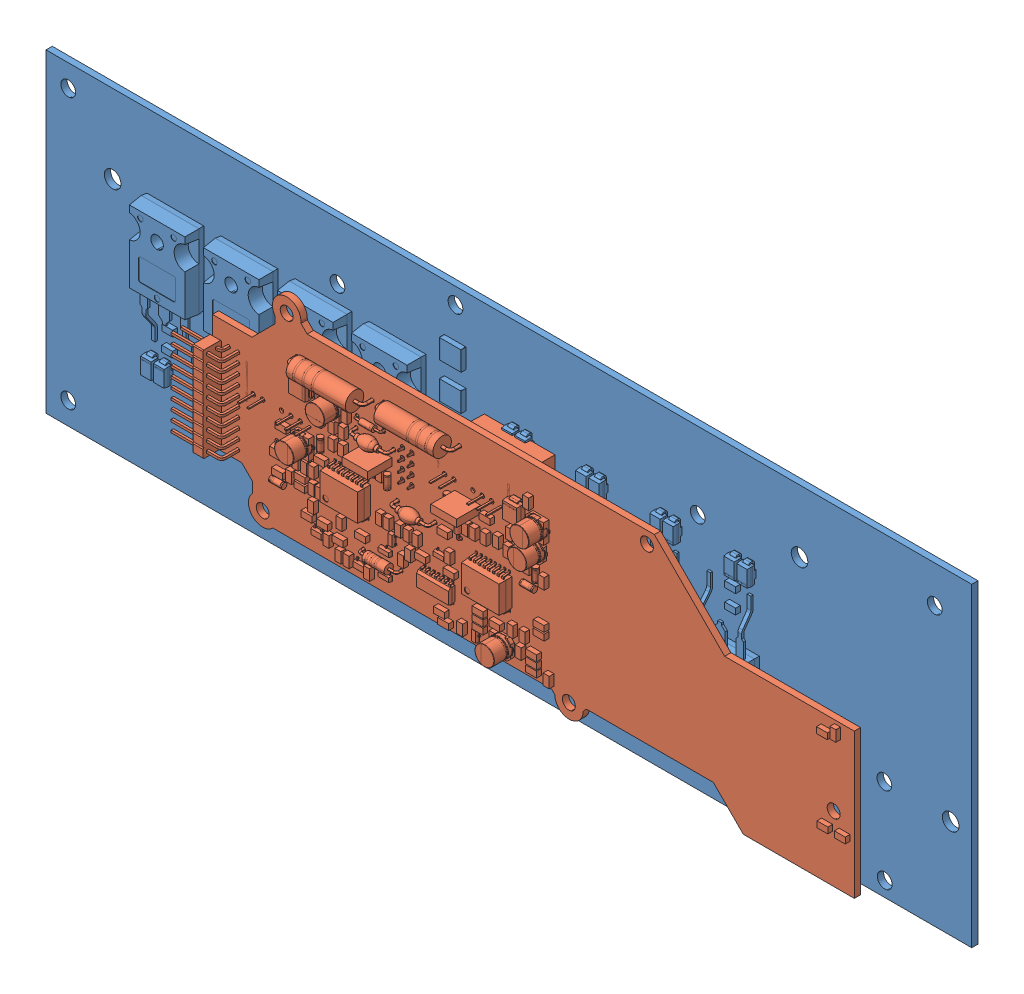
SolidWorks assembly M004Inv+driver, configuration Valor predeterminado. Lengths in mm.
Overall size (250 85 21.9).
2 component instances, 2 part files, 3 mates.
Components (placement in the parent):
- PL-001-V04 Inversor-1: PL-001-V04 Inversor [Default] at (-333.3909 -56.1521 -3.9803) size (250 85 11.34)
- PL-004-V04-1: PL-004-V04 [Valor predeterminado] at (-333.3909 -56.1521 9.7272) size (179.81 64.06 19)
Mates (geometry in assembly coordinates):
- Concêntrico1: concentric: cylinder of PL-001-V04 Inversor-1 through (-271.1609 -35.9591 -5.6717) axis (0 0 -1) radius 2; cylinder of PL-004-V04-1 through (-271.1609 -35.9591 8.0357) axis (0 0 -1) radius 1.75
- Concêntrico2: concentric: cylinder of PL-001-V04 Inversor-1 through (-264.6839 13.4439 -5.6717) axis (0 0 -1) radius 2; cylinder of PL-004-V04-1 through (-264.6839 13.4439 8.0357) axis (0 0 -1) radius 1.75
- Coincidente4: coincident: point of PL-001-V04 Inversor-1; plane of PL-004-V04-1 through (-232.0009 -9.9421 -0.4243) normal (0 0 -1)
